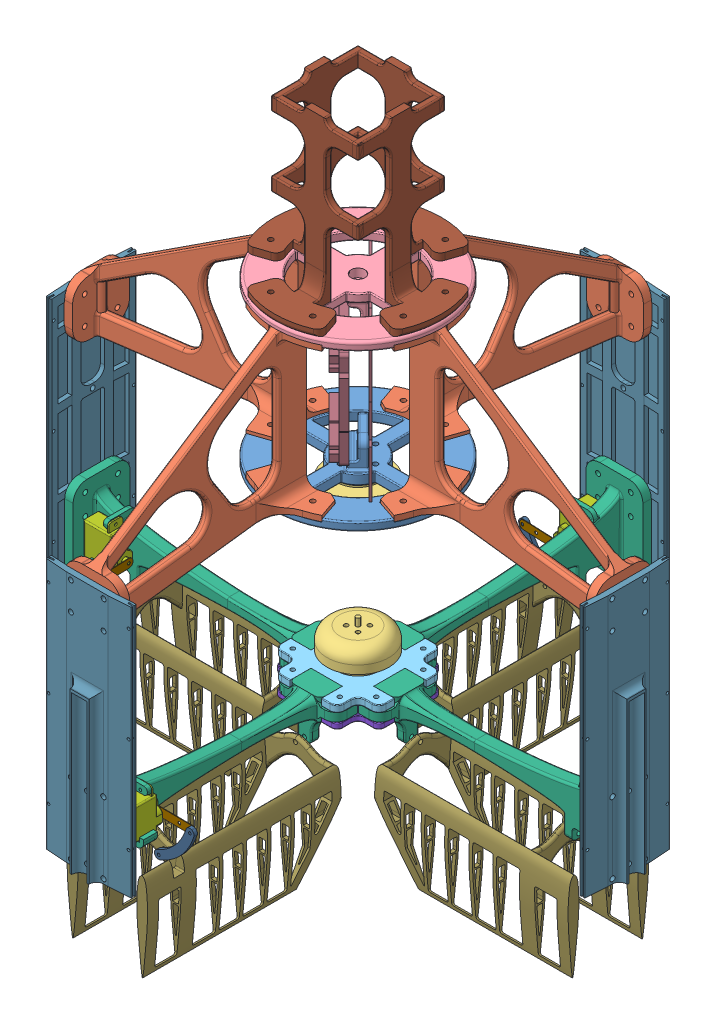
SolidWorks assembly drone, configuration Default. Lengths in mm.
Overall size (399.92 452.86 399.92).
36 component instances, 14 part files, 100 mates.
Components (placement in the parent):
- supportoMotore-1: supportoMotore [Default] x (-1 0 0) z (0 1 0) size (120 120 27)
- staffa-1: staffa [Default] at (-39.9375 0 3.0299) x (-1 0 0) z (0 0 -1) size (154.02 125 54.5)
- staffa-2: staffa [Default] at (39.9375 0 -2.9701) size (154.02 125 54.5)
- staffa-3: staffa [Default] at (3.0299 0 39.9375) x (0 0 1) z (-1 0 0) size (154.02 125 54.5)
- staffa-4: staffa [Default] at (-2.9701 0 -39.9375) x (0 0 -1) z (1 0 0) size (154.02 125 54.5)
- tmotor-1: tmotor [Default] at (0 -27 0) x (0 0 1) z (0 1 0) size (44.35 44.35 29.4)
- supportoStaffe-1: supportoStaffe [Default] at (0 110 0) x (1 0 0) z (0 -1 0) size (120 120 26)
- supportoMotoreInferiore-2: supportoMotoreInferiore [Default] at (0.0299 -130.5 0.0299) x (-1 0 0) z (0 1 0) size (75 75 5)
- tmotor-5: tmotor [Default] at (0.0299 -104.5 0.0299) x (0 0 -1) z (0 -1 0) size (44.35 44.35 29.4)
- staffaInferiore-1: staffaInferiore [Default] at (-189.9701 -136.5 11.2799) size (167.5 66 45)
- Szervo HS55-1: Szervo HS55 [Default] at (-180.4701 -132.3889 10.8299) x (0 -1 0) z (0 0 1) size (34.8 26.5 11.6)
- Szervo HS55-2: Szervo HS55 [Default] at (10.8299 -132.3889 180.5299) x (0 -1 0) z (1 0 0) size (34.8 26.5 11.6)
- staffaInferiore-2: staffaInferiore [Default] at (11.2799 -136.5 190.0299) x (0 0 -1) z (1 0 0) size (167.5 66 45)
- Szervo HS55-3: Szervo HS55 [Default] at (-10.7701 -132.3889 -180.4701) x (0 -1 0) z (-1 0 0) size (34.8 26.5 11.6)
- staffaInferiore-3: staffaInferiore [Default] at (-11.2201 -136.5 -189.9701) x (0 0 1) z (-1 0 0) size (167.5 66 45)
- Szervo HS55-4: Szervo HS55 [Default] at (180.5299 -132.3889 -10.7701) x (0 -1 0) z (0 0 -1) size (34.8 26.5 11.6)
- staffaInferiore-4: staffaInferiore [Default] at (190.0299 -136.5 -11.2201) x (-1 0 0) z (0 0 -1) size (167.5 66 45)
- supportoMotoreInferioreLight-1: supportoMotoreInferioreLight [Default] at (0.0299 -136.5 0.0299) x (1 0 0) z (0 -1 0) size (75 75 4)
- adattoreMotore - mezzo-1: adattoreMotore - mezzo [Default] at (-153.5701 -137.417 10.8299) x (0 -0.99925 -0.038729) z (0 0.038729 -0.99925) size (6 0.4 30)
- adattoreMotore - mezzo-2: adattoreMotore - mezzo [Default] at (10.8299 -137.417 153.6299) x (-0.007184 -0.999974 0) z (-0.999974 0.007184 0) size (6 0.4 30)
- adattoreMotore - mezzo-3: adattoreMotore - mezzo [Default] at (153.6299 -137.417 -10.7701) x (0 -0.999736 0.022997) z (0 0.022997 0.999736) size (6 0.4 30)
- adattoreMotore - mezzo-4: adattoreMotore - mezzo [Default] at (-10.7701 -137.417 -153.9701) x (0.04469 0.999001 0) z (0.999001 -0.04469 0) size (6 0.4 30)
- leveraggioDeflettore-1: leveraggioDeflettore [Default] at (-8.9683 -160.1989 -153.9701) x (-0.133879 -0.990998 0) z (0.990998 -0.133879 0) size (27.87 2.5 31.14)
- leveraggioDeflettore-2: leveraggioDeflettore [Default] at (154.0299 -161.202 -8.3872) x (0 -0.994084 -0.108617) z (0 -0.108617 0.994084) size (27.87 2.5 31.14)
- leveraggioDeflettore-3: leveraggioDeflettore [Default] at (8.5921 -160.9698 154.0299) x (0.114557 -0.993417 0) z (-0.993417 -0.114557 0) size (27.87 2.5 31.14)
- supportoBatteria-1: supportoBatteria [Default] at (-0.0214 172 26.2929) size (120 116.34 120)
- leveraggioDeflettore-5: leveraggioDeflettore [Default] at (-153.9701 -161.4314 8.2967) x (0 -0.994715 0.102679) z (0 -0.102679 -0.994715) size (27.87 2.5 31.14)
- deflettoreV4-1: deflettoreV4 [Default] at (0.0444 -157.5 96.5299) x (-0.999988 -0.004842 0) z (0 0 1) size (59.26 70 139.16)
- deflettoreV4-2: deflettoreV4 [Default] at (-96.4701 -157.4982 -0.0729) x (0 0.034272 -0.999413) z (-1 0 0) size (59.26 70 139.16)
- deflettoreV4-3: deflettoreV4 [Default] at (96.5299 -157.4997 0.074) x (0 0.014708 0.999892) z (1 0 0) size (59.26 70 139.16)
- deflettoreV4-4: deflettoreV4 [Default] at (-0.1745 -157.493 -96.4701) x (0.997676 -0.06814 0) z (0 0 -1) size (59.26 70 139.16)
- autopilota-2: autopilota [Default] at (5.0205 54.4342 -5.0205) x (0 -1 0) z (-0.707107 0 0.707107) size (96.5 96.5 21.7)
- staffa_laterale_light-1: staffa_laterale_light [Default] at (0.0299 -71.85 194.3625) x (-1 0 0) z (0 0 -1) size (61 180.7 10.4)
- staffa_laterale_light-3: staffa_laterale_light [Default] at (194.3625 -71.85 0.0299) x (0 0 1) z (-1 0 0) size (61 180.7 10.4)
- staffa_laterale_light-4: staffa_laterale_light [Default] at (0.0299 -71.85 -194.3625) size (61 180.7 10.4)
- staffa_laterale_light-5: staffa_laterale_light [Default] at (-194.3625 -71.85 0.0299) x (0 0 -1) z (1 0 0) size (61 180.7 10.4)
Mates (geometry in assembly coordinates):
- Concentrico1: concentric anti-aligned: cylinder of supportoMotore-1 through (47.5579 -4.001 15.0334) axis (0 1 0) radius 2; cylinder of staffa-2 through (47.5579 4 15.0334) axis (0 -1 0) radius 1.75
- Coincidente1: coincident anti-aligned: plane of supportoMotore-1 through (0 0 0) normal (0 1 0); plane of staffa-2 through (39.9375 0 3.0299) normal (0 -1 0)
- Concentrico10: concentric anti-aligned: cylinder of supportoMotore-1 through (-47.5579 -4.001 15.0334) axis (0 1 0) radius 2; cylinder of staffa-1 through (-47.5579 4 15.0334) axis (0 -1 0) radius 1.75
- Parallelo5: parallel anti-aligned: plane of staffa-1 through (-39.9375 0 -2.9701) normal (1 0 0); plane of staffa-2 through (39.9375 0 3.0299) normal (-1 0 0)
- Concentrico11: concentric anti-aligned: cylinder of supportoMotore-1 through (15.0334 -4.001 47.5579) axis (0 1 0) radius 2; cylinder of staffa-3 through (15.0334 4 47.5579) axis (0 -1 0) radius 1.75
- Concentrico12: concentric anti-aligned: cylinder of supportoMotore-1 through (15.0334 -4.001 -47.5579) axis (0 1 0) radius 2; circle of staffa-4
- Parallelo6: parallel anti-aligned: plane of staffa-3 through (-2.9701 0 39.9375) normal (0 0 -1); plane of staffa-4 through (3.0299 0 -39.9375) normal (0 0 1)
- Coincidente5: coincident anti-aligned: plane of supportoMotore-1 through (0 0 0) normal (0 1 0); plane of staffa-4 through (3.0299 0 -39.9375) normal (0 -1 0)
- Coincidente6: coincident anti-aligned: plane of supportoMotore-1 through (0 0 0) normal (0 1 0); plane of staffa-1 through (-39.9375 0 -2.9701) normal (0 -1 0)
- Perpendicolare1: perpendicular: plane of staffa-2 through (39.9375 0 3.0299) normal (-1 0 0); plane of staffa-3 through (-2.9701 0 39.9375) normal (0 0 -1)
- Perpendicolare2: perpendicular: plane of supportoMotore-1 through (0 -5 -5) normal (0 0 -1); plane of staffa-2 through (39.9375 0 3.0299) normal (-1 0 0)
- Concentrico19: concentric aligned: cylinder of supportoMotore-1 through (12.5 -4.001 0) axis (0 1 0) radius 1.75; cylinder of tmotor-1 through (12.5 -27.001 0) axis (0 1 0) radius 1.5
- Concentrico20: concentric aligned: cylinder of supportoMotore-1 through (0 -4.001 -12.5) axis (0 1 0) radius 1.75; cylinder of tmotor-1 through (0 -27.001 -12.5) axis (0 1 0) radius 1.5
- Coincidente10: coincident anti-aligned: plane of supportoMotore-1 through (0 -6 0) normal (0 -1 0); plane of tmotor-1 through (0 -6 0) normal (0 1 0)
- Concentrico21: concentric anti-aligned: cylinder of supportoMotoreInferiore-2 through (16.9049 -135.5 30.0299) axis (0 1 0) radius 1.5; cylinder of staffaInferiore-2 through (16.9049 -130.5 30.0299) axis (0 -1 0) radius 1.5
- Concentrico22: concentric aligned: circle of staffaInferioreV1.2 - Copia-2; cylinder of supportoMotoreInferioreLight-1 through (16.9049 -130.5 30.0299) axis (0 -1 0) radius 1.5
- Concentrico23: concentric aligned: cylinder of staffaInferiore-2 through (-16.8451 -130.5 30.0299) axis (0 -1 0) radius 1.5; cylinder of supportoMotoreInferioreLight-1 through (-16.8451 -130.5 30.0299) axis (0 -1 0) radius 1.5
- Concentrico24: concentric anti-aligned: circle of supportoMotoreInferioreV1.1-2; cylinder of staffaInferiore-2 through (-16.8451 -130.5 30.0299) axis (0 -1 0) radius 1.5
- Concentrico25: concentric anti-aligned: cylinder of supportoMotoreInferiore-2 through (-29.9701 -135.5 16.9049) axis (0 1 0) radius 1.5; cylinder of staffaInferiore-1 through (-29.9701 -130.5 16.9049) axis (0 -1 0) radius 1.5
- Concentrico26: concentric aligned: cylinder of staffaInferiore-1 through (-29.9701 -130.5 16.9049) axis (0 -1 0) radius 1.5; cylinder of supportoMotoreInferioreLight-1 through (-29.9701 -130.5 16.9049) axis (0 -1 0) radius 1.5
- Concentrico27: concentric anti-aligned: cylinder of supportoMotoreInferiore-2 through (-29.9701 -135.5 -16.8451) axis (0 1 0) radius 1.5; cylinder of staffaInferiore-1 through (-29.9701 -130.5 -16.8451) axis (0 -1 0) radius 1.5
- Concentrico28: concentric aligned: cylinder of staffaInferiore-1 through (-29.9701 -130.5 -16.8451) axis (0 -1 0) radius 1.5; cylinder of supportoMotoreInferioreLight-1 through (-29.9701 -130.5 -16.8451) axis (0 -1 0) radius 1.5
- Concentrico29: concentric aligned: cylinder of staffaInferiore-3 through (-16.8451 -130.5 -29.9701) axis (0 -1 0) radius 1.5; cylinder of supportoMotoreInferioreLight-1 through (-16.8451 -130.5 -29.9701) axis (0 -1 0) radius 1.5
- Concentrico30: concentric anti-aligned: cylinder of supportoMotoreInferiore-2 through (-16.8451 -135.5 -29.9701) axis (0 1 0) radius 1.5; cylinder of staffaInferiore-3 through (-16.8451 -130.5 -29.9701) axis (0 -1 0) radius 1.5
- Concentrico31: concentric anti-aligned: cylinder of supportoMotoreInferiore-2 through (16.9049 -135.5 -29.9701) axis (0 1 0) radius 1.5; cylinder of staffaInferiore-3 through (16.9049 -130.5 -29.9701) axis (0 -1 0) radius 1.5
- Concentrico32: concentric aligned: cylinder of staffaInferiore-3 through (16.9049 -130.5 -29.9701) axis (0 -1 0) radius 1.5; cylinder of supportoMotoreInferioreLight-1 through (16.9049 -130.5 -29.9701) axis (0 -1 0) radius 1.5
- Coincidente14: coincident anti-aligned: plane of supportoMotoreInferiore-2 through (0.0299 -130.5 0.0299) normal (0 -1 0); plane of staffaInferiore-4 through (190.0299 -130.5 -11.2201) normal (0 1 0)
- Coincidente15: coincident anti-aligned: plane of supportoMotoreInferiore-2 through (0.0299 -130.5 0.0299) normal (0 -1 0); plane of staffaInferiore-3 through (-11.2201 -130.5 -189.9701) normal (0 1 0)
- Coincidente16: coincident anti-aligned: plane of supportoMotoreInferiore-2 through (0.0299 -130.5 0.0299) normal (0 -1 0); plane of staffaInferiore-1 through (-189.9701 -130.5 11.2799) normal (0 1 0)
- Coincidente17: coincident: line of supportoMotoreInferiore-2 through (12.2799 -130.5 22.5299) axis (-1 0 0); plane of staffaInferiore-2 through (11.2799 -130.5 190.0299) normal (0 1 0)
- Coincidente18: coincident anti-aligned: plane of staffaInferiore-1 through (-189.9701 -136.5 11.2799) normal (0 -1 0); plane of supportoMotoreInferioreLight-1 through (0.0299 -136.5 0.0299) normal (0 1 0)
- Concentrico33: concentric anti-aligned: cylinder of Szervo HS55-1 through (-155.9701 -137.417 10.8299) axis (-1 0 0) radius 2.5; cylinder of adattoreMotore - mezzo-1 through (-153.9701 -137.417 10.8299) axis (1 0 0) radius 1
- Concentrico34: concentric aligned: cylinder of staffaInferiore-1 through (-168.9701 -117.8889 10.8299) axis (1 0 0) radius 1; cylinder of Szervo HS55-1 through (-180.4701 -117.8889 10.8299) axis (1 0 0) radius 1
- Coincidente19: coincident anti-aligned: plane of staffaInferiore-1 through (-163.9701 -136.5 -4.9701) normal (1 0 0); plane of Szervo HS55-1 through (-163.9701 -120.9889 15.8299) normal (-1 0 0)
- Coincidente23: coincident anti-aligned: plane of Szervo HS55-1 through (-153.9701 -137.417 10.8299) normal (1 0 0); plane of adattoreMotore - mezzo-1 through (-153.9701 -137.417 10.8299) normal (-1 0 0)
- Concentrico41: concentric anti-aligned: circle of supportoMotoreInferioreV1.1-2; cylinder of tmotor-5 through (0.0299 -104.499 12.5299) axis (0 -1 0) radius 1.5
- Concentrico42: concentric aligned: cylinder of supportoMotoreInferiore-2 through (-12.4701 -125.5 0.0299) axis (0 -1 0) radius 1.5; cylinder of tmotor-5 through (-12.4701 -104.499 0.0299) axis (0 -1 0) radius 1.5
- Coincidente27: coincident anti-aligned: plane of supportoMotoreInferiore-2 through (0.0299 -125.5 0.0299) normal (0 1 0); plane of tmotor-5 through (0.0299 -125.5 0.0299) normal (0 -1 0)
- Concentrico44: concentric anti-aligned: cylinder of supportoMotoreInferiore-2 through (30.0299 -135.5 16.9049) axis (0 1 0) radius 1.5; cylinder of staffaInferiore-4 through (30.0299 -130.5 16.9049) axis (0 -1 0) radius 1.5
- Concentrico45: concentric anti-aligned: cylinder of supportoMotoreInferiore-2 through (30.0299 -135.5 -16.8451) axis (0 1 0) radius 1.5; cylinder of staffaInferiore-4 through (30.0299 -130.5 -16.8451) axis (0 -1 0) radius 1.5
- Concentrico47: concentric anti-aligned: circle of Szervo HS55-2; cylinder of staffaInferiore-2 through (10.8299 -117.8889 169.0299) axis (0 0 -1) radius 1
- Coincidente32: coincident anti-aligned: plane of Szervo HS55-2 through (15.8299 -120.9889 164.0299) normal (0 0 1); plane of staffaInferiore-2 through (-4.9701 -136.5 164.0299) normal (0 0 -1)
- Concentrico48: concentric anti-aligned: cylinder of Szervo HS55-2 through (10.8299 -137.417 156.0299) axis (0 0 1) radius 2.5; cylinder of adattoreMotore - mezzo-2 through (10.8299 -137.417 154.0299) axis (0 0 -1) radius 1
- Coincidente34: coincident anti-aligned: plane of Szervo HS55-2 through (10.8299 -137.417 154.0299) normal (0 0 -1); plane of adattoreMotore - mezzo-2 through (10.8299 -137.417 154.0299) normal (0 0 1)
- Concentrico49: concentric aligned: cylinder of adattoreMotore - mezzo-2 through (35.8292 -137.5966 154.0299) axis (0 0 -1) radius 1; cylinder of leveraggioDeflettore-3 through (35.8292 -137.5966 156.5299) axis (0 0 -1) radius 0.9362
- Coincidente37: coincident anti-aligned: plane of adattoreMotore - mezzo-2 through (10.8299 -137.417 154.0299) normal (0 0 1); plane of leveraggioDeflettore-3 through (-2.9051 -124.9633 154.0299) normal (0 0 -1)
- Concentrico59: concentric aligned: cylinder of Szervo HS55-3 through (-10.7701 -117.8889 -180.4701) axis (0 0 1) radius 1; cylinder of staffaInferiore-3 through (-10.7701 -117.8889 -168.9701) axis (0 0 1) radius 1
- Coincidente43: coincident anti-aligned: plane of Szervo HS55-3 through (-4.9701 -143.7889 -160.4701) normal (1 0 0); plane of staffaInferiore-3 through (-4.9701 -130.5 -189.9701) normal (-1 0 0)
- Coincidente44: coincident anti-aligned: plane of Szervo HS55-3 through (-15.7701 -120.9889 -163.9701) normal (0 0 -1); plane of staffaInferiore-3 through (5.0299 -136.5 -163.9701) normal (0 0 1)
- Concentrico60: concentric aligned: cylinder of Szervo HS55-3 through (-10.7701 -137.417 -155.9701) axis (0 0 -1) radius 2.5; cylinder of adattoreMotore - mezzo-4 through (-10.7701 -137.417 -153.5701) axis (0 0 -1) radius 1
- Coincidente45: coincident anti-aligned: plane of Szervo HS55-3 through (-10.7701 -137.417 -153.9701) normal (0 0 1); plane of adattoreMotore - mezzo-4 through (-10.7701 -137.417 -153.9701) normal (0 0 -1)
- Concentrico61: concentric anti-aligned: cylinder of adattoreMotore - mezzo-4 through (-35.7452 -136.2997 -153.5701) axis (0 0 -1) radius 1; cylinder of leveraggioDeflettore-1 through (-35.7452 -136.2997 -156.4701) axis (0 0 1) radius 0.9362
- Coincidente47: coincident anti-aligned: plane of adattoreMotore - mezzo-4 through (-10.7701 -137.417 -153.9701) normal (0 0 -1); plane of leveraggioDeflettore-1 through (3.2278 -124.423 -153.9701) normal (0 0 1)
- Concentrico64: concentric aligned: cylinder of Szervo HS55-4 through (180.5299 -117.8889 -10.7701) axis (-1 0 0) radius 1; cylinder of staffaInferiore-4 through (169.0299 -117.8889 -10.7701) axis (-1 0 0) radius 1
- Coincidente50: coincident anti-aligned: plane of Szervo HS55-4 through (164.0299 -120.9889 -15.7701) normal (1 0 0); plane of staffaInferiore-4 through (164.0299 -136.5 5.0299) normal (-1 0 0)
- Coincidente51: coincident anti-aligned: plane of Szervo HS55-4 through (160.5299 -143.7889 -4.9701) normal (0 0 1); plane of staffaInferiore-4 through (190.0299 -130.5 -4.9701) normal (0 0 -1)
- Concentrico65: concentric anti-aligned: cylinder of Szervo HS55-4 through (156.0299 -137.417 -10.7701) axis (1 0 0) radius 2.5; cylinder of adattoreMotore - mezzo-3 through (154.0299 -137.417 -10.7701) axis (-1 0 0) radius 1
- Concentrico66: concentric aligned: cylinder of adattoreMotore - mezzo-3 through (154.0299 -137.9919 -35.7635) axis (-1 0 0) radius 1; cylinder of leveraggioDeflettore-2 through (156.5299 -137.9919 -35.7635) axis (-1 0 0) radius 0.9362
- Coincidente52: coincident anti-aligned: plane of adattoreMotore - mezzo-3 through (154.0299 -137.417 -10.7701) normal (1 0 0); plane of leveraggioDeflettore-2 through (154.0299 -125.1273 2.8946) normal (-1 0 0)
- Concentrico68: concentric aligned: circle of staffa-2; circle of supportoStaffe-1
- Concentrico70: concentric anti-aligned: cylinder of supportoMotore-1 through (0 -6 0) axis (0 1 0) radius 17.5; cylinder of supportoStaffe-1 through (0 114 0) axis (0 -1 0) radius 5
- Coincidente54: coincident anti-aligned: plane of staffa-4 through (3.0299 110 -39.9375) normal (0 1 0); plane of supportoStaffe-1 through (0 110 0) normal (0 -1 0)
- Coincidente59: coincident anti-aligned: plane of supportoMotore-1 through (0 0 0) normal (0 1 0); plane of staffa-3 through (-2.9701 0 39.9375) normal (0 -1 0)
- Coincidente64: coincident anti-aligned: plane of Szervo HS55-4 through (154.0299 -137.417 -10.7701) normal (-1 0 0); plane of adattoreMotore - mezzo-3 through (154.0299 -137.417 -10.7701) normal (1 0 0)
- Concentrico91: concentric aligned: cylinder of supportoStaffe-1 through (47.5579 114.001 15.0334) axis (0 -1 0) radius 1.75; cylinder of suppBattCortoUnico-1 through (47.5579 119 15.0334) axis (0 -1 0) radius 1.75
- Coincidente85: coincident anti-aligned: plane of supportoStaffe-1 through (0 114 0) normal (0 1 0); plane of suppBattCortoUnico-1 through (-0.0214 114 -0.0071) normal (0 -1 0)
- Parallelo15: parallel aligned: plane of staffa-2 through (39.9375 0 -2.9701) normal (0 0 -1); plane of suppBattCortoUnico-1 through (-0.0214 172 -31.3071) normal (0 0 -1)
- Concentrico98: concentric aligned: cylinder of adattoreMotore - mezzo-1 through (-153.9701 -138.3852 35.8111) axis (1 0 0) radius 1; cylinder of leveraggioDeflettore-5 through (-156.4701 -138.3852 35.8111) axis (1 0 0) radius 0.9362
- Coincidente91: coincident anti-aligned: plane of adattoreMotore - mezzo-1 through (-153.9701 -137.417 10.8299) normal (-1 0 0); plane of leveraggioDeflettore-5 through (-153.9701 -125.29 -2.7695) normal (1 0 0)
- Coincidente107: coincident anti-aligned: plane of staffaInferiore-1 through (-189.9701 -130.5 5.0299) normal (0 0 1); plane of Szervo HS55-1 through (-160.4701 -143.7889 5.0299) normal (0 0 -1)
- Coincidente111: coincident anti-aligned: plane of Szervo HS55-2 through (5.0299 -143.7889 160.5299) normal (-1 0 0); plane of staffaInferiore-2 through (5.0299 -130.5 190.0299) normal (1 0 0)
- Concentrico107: concentric aligned: cylinder of staffaInferiore-2 through (0.0299 -154.5 22.5299) axis (0 0 1) radius 1.5; cylinder of deflettoreV4-1 through (0.0299 -154.5 136.103) axis (0 0 1) radius 1.5
- Concentrico108: concentric anti-aligned: cylinder of leveraggioDeflettore-3 through (13.4671 -162.165 156.5299) axis (0 0 -1) radius 1; cylinder of deflettoreV4-1 through (13.4671 -162.165 41.0288) axis (0 0 1) radius 1.25
- Coincidente112: coincident anti-aligned: plane of leveraggioDeflettore-3 through (-2.9051 -124.9633 154.0299) normal (0 0 -1); plane of deflettoreV4-1 through (0.0444 -157.5 154.0299) normal (0 0 1)
- Concentrico110: concentric aligned: cylinder of staffaInferiore-1 through (-22.4701 -154.5 0.0299) axis (-1 0 0) radius 1.5; cylinder of deflettoreV4-2 through (-136.0433 -154.5 0.0299) axis (-1 0 0) radius 1.5
- Concentrico111: concentric aligned: circle of leveraggioDeflettore-5; cylinder of deflettoreV4-2 through (-40.9691 -162.6847 13.1571) axis (-1 0 0) radius 1.25
- Coincidente113: coincident anti-aligned: plane of leveraggioDeflettore-5 through (-153.9701 -125.29 -2.7695) normal (1 0 0); plane of deflettoreV4-2 through (-153.9701 -157.4982 -0.0729) normal (-1 0 0)
- Concentrico112: concentric aligned: cylinder of staffaInferiore-4 through (22.5299 -154.5 0.0299) axis (1 0 0) radius 1.5; cylinder of deflettoreV4-3 through (136.103 -154.5 0.0299) axis (1 0 0) radius 1.5
- Concentrico113: concentric anti-aligned: cylinder of leveraggioDeflettore-2 through (156.5299 -162.4262 -13.255) axis (-1 0 0) radius 1; cylinder of deflettoreV4-3 through (41.0288 -162.4262 -13.255) axis (1 0 0) radius 1.25
- Coincidente114: coincident anti-aligned: plane of leveraggioDeflettore-2 through (154.0299 -125.1273 2.8946) normal (-1 0 0); plane of deflettoreV4-3 through (154.0299 -157.4997 0.074) normal (1 0 0)
- Concentrico114: concentric aligned: cylinder of staffaInferiore-3 through (0.0299 -154.5 -22.4701) axis (0 0 -1) radius 1.5; cylinder of deflettoreV4-4 through (0.0299 -154.5 -136.0433) axis (0 0 -1) radius 1.5
- Concentrico115: concentric aligned: circle of leveraggioDeflettore-1; circle of deflettoreV4-4
- Coincidente115: coincident anti-aligned: plane of leveraggioDeflettore-1 through (3.2278 -124.423 -153.9701) normal (0 0 1); plane of deflettoreV4-4 through (-0.1745 -157.493 -153.9701) normal (0 0 -1)
- Concentrico116: concentric aligned: cylinder of supportoMotore-1 through (54.185 17.5592 -65.817) axis (-0.707107 0 0.707107) radius 1.775; cylinder of autopilota-2 through (-0.7955 17.5592 -10.8364) axis (-0.707107 0 0.707107) radius 1.775
- Concentrico117: concentric aligned: cylinder of supportoStaffe-1 through (65.817 91.3092 -54.185) axis (-0.707107 0 0.707107) radius 1.775; cylinder of autopilota-2 through (10.8364 91.3092 0.7955) axis (-0.707107 0 0.707107) radius 1.775
- Coincidente116: coincident anti-aligned: plane of supportoStaffe-1 through (3.8891 88 -3.8891) normal (0.707107 0 -0.707107); plane of autopilota-2 through (3.8891 54.4342 -3.8891) normal (-0.707107 0 0.707107)
- Concentrico122: concentric aligned: cylinder of staffa-3 through (11.7799 15 184.3625) axis (0 0 1) radius 1.75; cylinder of staffa_laterale_light-1 through (11.7799 15 190.3625) axis (0 0 1) radius 1.75
- Concentrico123: concentric aligned: cylinder of staffa-3 through (-11.7201 15 184.3625) axis (0 0 1) radius 1.75; cylinder of staffa_laterale_light-1 through (-11.7201 15 190.3625) axis (0 0 1) radius 1.75
- Coincidente124: coincident anti-aligned: plane of staffa-3 through (-2.9701 0 190.3625) normal (0 0 1); plane of staffa_laterale_light-1 through (0.0299 -71.85 190.3625) normal (0 0 -1)
- Concentrico124: concentric aligned: cylinder of staffaInferiore-2 through (11.7799 -159 184.0299) axis (0 0 1) radius 1.75; cylinder of staffa_laterale_light-1 through (11.7799 -159 190.3625) axis (0 0 1) radius 1.75
- Coincidente125: coincident aligned: circle of staffa-2; cylinder of staffa_laterale_light-3 through (190.3625 15 11.7799) axis (1 0 0) radius 1.75
- Concentrico125: concentric aligned: cylinder of staffa-2 through (184.3625 15 -11.7201) axis (1 0 0) radius 1.75; cylinder of staffa_laterale_light-3 through (190.3625 15 -11.7201) axis (1 0 0) radius 1.75
- Coincidente126: coincident anti-aligned: plane of staffa-2 through (190.3625 0 3.0299) normal (1 0 0); plane of staffa_laterale_light-3 through (190.3625 -71.85 0.0299) normal (-1 0 0)
- Concentrico126: concentric aligned: cylinder of staffaInferiore-4 through (184.0299 -159 11.7799) axis (1 0 0) radius 1.75; cylinder of staffa_laterale_light-3 through (190.3625 -159 11.7799) axis (1 0 0) radius 1.75
- Concentrico127: concentric anti-aligned: circle of staffa-4; circle of staffa_laterale_light-4
- Concentrico128: concentric anti-aligned: cylinder of staffaInferiore-3 through (-11.7201 -108 -183.9701) axis (0 0 -1) radius 1.75; circle of staffa_laterale_light-4
- Coincidente129: coincident anti-aligned: plane of staffa-4 through (3.0299 0 -190.3625) normal (0 0 -1); plane of staffa_laterale_light-4 through (0.0299 -71.85 -190.3625) normal (0 0 1)
- Concentrico129: concentric aligned: cylinder of staffa-1 through (-184.3625 -5 -11.7201) axis (-1 0 0) radius 1.75; cylinder of staffa_laterale_light-5 through (-190.3625 -5 -11.7201) axis (-1 0 0) radius 1.75
- Concentrico130: concentric aligned: cylinder of staffa-1 through (-184.3625 -5 11.7799) axis (-1 0 0) radius 1.75; cylinder of staffa_laterale_light-5 through (-190.3625 -5 11.7799) axis (-1 0 0) radius 1.75
- Coincidente130: coincident: plane of staffa-1 through (-190.3625 0 -2.9701) normal (-1 0 0); line of staffa_laterale_light-5 through (-190.3625 11.5 6.5799) axis (0 0 -1)
